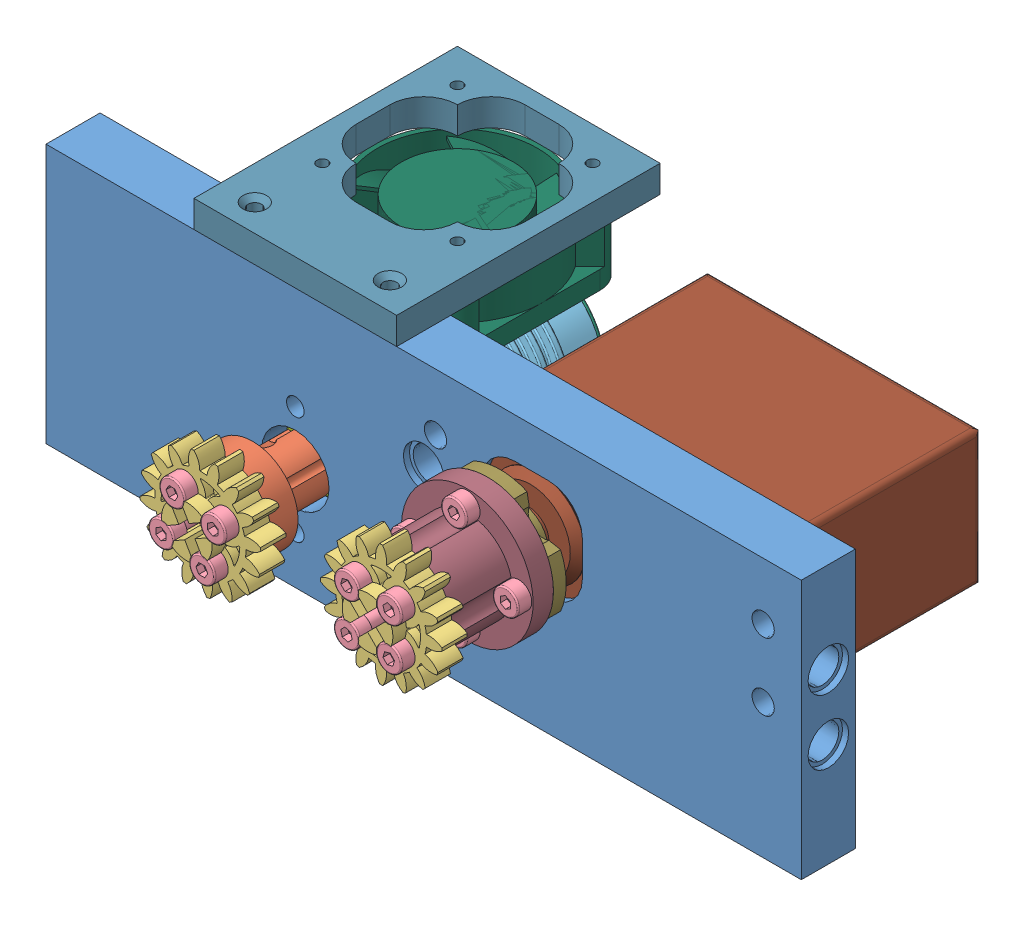
SolidWorks assembly Antriebseinheit, configuration Standard. Lengths in mm.
Overall size (111.8 42.91 67.55).
31 component instances, 15 part files, 21 mates.
Components (placement in the parent):
- Aufnahme-Motoren-1: Aufnahme-Motoren [Standard] x (-1 0 0) z (0 0 -1) size (111.8 38.4 8)
- Adapter-Motor-Zahnrad-16Z-1: Adapter-Motor-Zahnrad-16Z [Standard] at (-18.9984 15.2 10.3) x (-0.866025 -0.5 0) z (0 0 1) size (18 18 17.55)
  - Adapter-Motor-Zahnrad-16Z-1: Adapter-Motor-Zahnrad-16Z [Standard] at origin size (13.4 13.4 11.8)
  - Lego Zahnrad 16Z-1: Lego Zahnrad 16Z [Standard] at (0 0 5.875) size (18 18 7.75)
  - DIN 912 M2 x 6 --- 6N-1: DIN 912 M2 x 6 --- 6N [DIN 912 M2 x 6 --- 6N] at (0 4.425 9.75) x (0 0 -1) z (1 0 0) size (8 3.8 3.8)
  - DIN 912 M2 x 6 --- 6N-2: DIN 912 M2 x 6 --- 6N [DIN 912 M2 x 6 --- 6N] at (4.425 0 9.75) x (0 0 -1) z (0 -1 0) size (8 3.8 3.8)
  - DIN 912 M2 x 6 --- 6N-3: DIN 912 M2 x 6 --- 6N [DIN 912 M2 x 6 --- 6N] at (0 -4.425 9.75) x (0 0 -1) z (-1 0 0) size (8 3.8 3.8)
  - DIN 912 M2 x 6 --- 6N-4: DIN 912 M2 x 6 --- 6N [DIN 912 M2 x 6 --- 6N] at (-4.425 0 9.75) x (0 0 -1) z (0 1 0) size (8 3.8 3.8)
- Motor_B20-30-24S-FIN-1: Motor_B20-30-24S-FIN [Standard] at (-18.9984 15.2 -17) x (-0.866025 -0.5 0) z (0 0 1) size (23 23 51)
  - Motor_B20-30-24S-FIN-Gehaeuse-1: Motor_B20-30-24S-FIN-Gehaeuse [Standard] at origin size (23 23 29)
  - Motor_B20-30-24S-FIN-FlanschHinten-1: Motor_B20-30-24S-FIN-FlanschHinten [Standard] at (0 0 -15) x (0 -1 0) z (0 0 1) size (20 20 11)
  - Motor_B20-30-24S-FIN-FlanschVorne-1: Motor_B20-30-24S-FIN-FlanschVorne [Standard] at (0 0 14.5) x (0 -1 0) z (0 0 1) size (20 20 5)
  - Motor_B20-30-24S-FIN-Rotorwelle-1: Motor_B20-30-24S-FIN-Rotorwelle [Standard] at (0 0 -16.5) x (1 0 0) z (0 -1 0) size (5 45 5)
  - Motor_B20-30-24S-FIN-Lager-1: Motor_B20-30-24S-FIN-Lager [Standard] at (0 0 -12.5) x (0 0 -1) z (0 1 0) size (4 8 8)
  - Motor_B20-30-24S-FIN-Lager-2: Motor_B20-30-24S-FIN-Lager [Standard] at (0 0 16.5) x (0 0 -1) z (0 1 0) size (4 8 8)
  - Motor_B20-30-24S-FIN-Masse-1: Motor_B20-30-24S-FIN-Masse [Standard] at origin size (15 15 15)
- Servo HK15138-1: Servo HK15138 [Standard] at (26 24.95 -32.8) x (1 0 0) z (0 -1 0) size (55.5 41.1 20.15)
- Adapter-Servo-Zahnrad-16Z-1: Adapter-Servo-Zahnrad-16Z [Standard] at (15.75 24.95 8.5) size (27.58 27.58 22.65)
  - Servo-Horn-4er-modifiziert-1: Servo-Horn-4er-modifiziert [Standard] at origin size (19.5 19.5 5.7)
  - Adapter-Servo-Zahnrad-16Z-1: Adapter-Servo-Zahnrad-16Z [Standard] at (0 0 4.8) x (-0.707107 0.707107 0) z (0 0 1) size (19.5 19.5 12)
  - Lego Zahnrad 16Z-1: Lego Zahnrad 16Z [Standard] at (0 0 15.675) x (-0.707107 0.707107 0) z (0 0 1) size (18 18 7.75)
  - DIN 912 M2 x 6 --- 6N-1: DIN 912 M2 x 6 --- 6N [DIN 912 M2 x 6 --- 6N] at (-3.1289 -3.1289 19.55) x (0 0 -1) z (-0.707107 0.707107 0) size (8 3.8 3.8)
  - DIN 912 M2 x 6 --- 6N-2: DIN 912 M2 x 6 --- 6N [DIN 912 M2 x 6 --- 6N] at (-3.1289 3.1289 19.55) x (0 0 -1) z (0.707107 0.707107 0) size (8 3.8 3.8)
  - DIN 912 M2 x 6 --- 6N-3: DIN 912 M2 x 6 --- 6N [DIN 912 M2 x 6 --- 6N] at (3.1289 3.1289 19.55) x (0 0 -1) z (0.707107 -0.707107 0) size (8 3.8 3.8)
  - DIN 912 M2 x 6 --- 6N-4: DIN 912 M2 x 6 --- 6N [DIN 912 M2 x 6 --- 6N] at (3.1289 -3.1289 19.55) x (0 0 -1) z (-0.707107 -0.707107 0) size (8 3.8 3.8)
  - DIN 912 M2 x 6 --- 6N-5: DIN 912 M2 x 6 --- 6N [DIN 912 M2 x 6 --- 6N] at (0 7.65 6.8) x (0 0 -1) z (0 1 0) size (8 3.8 3.8)
  - DIN 912 M2 x 6 --- 6N-6: DIN 912 M2 x 6 --- 6N [DIN 912 M2 x 6 --- 6N] at (7.65 0 6.8) x (0 0 -1) z (1 0 0) size (8 3.8 3.8)
  - DIN 912 M2 x 6 --- 6N-7: DIN 912 M2 x 6 --- 6N [DIN 912 M2 x 6 --- 6N] at (0 -7.65 6.8) x (0 0 -1) z (0 -1 0) size (8 3.8 3.8)
  - DIN 912 M2 x 6 --- 6N-8: DIN 912 M2 x 6 --- 6N [DIN 912 M2 x 6 --- 6N] at (-7.65 0 6.8) x (0 0 -1) z (-1 0 0) size (8 3.8 3.8)
- Aufnahme-Lüfter-1: Aufnahme-Lüfter [Standard] at (-18.9984 38.4 -20) x (-1 0 0) z (0 0 -1) size (30 4 39)
- Hobby King X-Car 60A Brushless Car ESC - Lüfter-1: Hobby King X-Car 60A Brushless Car ESC - Lüfter [Ohne Stecker] at (-18.9984 28.1 -20) size (25.1 10.44 25.1)
Mates (geometry in assembly coordinates):
- Deckungsgleich1: coincident anti-aligned: plane of Aufnahme-Motoren-1 through (0 0 0) normal (0 0 -1); plane of assembly through (0 0 0) normal (0 0 1)
- Deckungsgleich2: coincident aligned: plane of Aufnahme-Motoren-1; plane of assembly through (0 0 0) normal (0 1 0)
- Deckungsgleich3: coincident anti-aligned: plane of Aufnahme-Motoren-1 through (0 0 0) normal (-1 0 0); plane of assembly through (0 0 0) normal (1 0 0)
- Deckungsgleich4: coincident anti-aligned: plane of Aufnahme-Motoren-1 through (0 0 -2) normal (0 0 -1); plane of Motor_B20-30-24S-FIN-1/Motor_B20-30-24S-FIN-FlanschVorne-1 through (-18.9984 15.2 -2) normal (0 0 1)
- Konzentrisch1: concentric anti-aligned: cylinder of Aufnahme-Motoren-1 through (-18.9984 23.2 4) axis (0 0 -1) radius 1.3; cylinder of Motor_B20-30-24S-FIN-1/Motor_B20-30-24S-FIN-FlanschVorne-1 through (-18.9984 23.2 -30.3945) axis (0 0 1) radius 1.0065
- Konzentrisch2: concentric anti-aligned: cylinder of Aufnahme-Motoren-1 through (-18.9984 7.2 4) axis (0 0 -1) radius 1.3; cylinder of Motor_B20-30-24S-FIN-1/Motor_B20-30-24S-FIN-FlanschVorne-1 through (-18.9984 7.2 -30.3945) axis (0 0 1) radius 1.0065
- Konzentrisch3: concentric anti-aligned: cylinder of Adapter-Motor-Zahnrad-16Z-1/Adapter-Motor-Zahnrad-16Z-1 through (-18.9984 15.2 2.5) axis (0 0 1) radius 1; cylinder of Motor_B20-30-24S-FIN-1/Motor_B20-30-24S-FIN-Rotorwelle-1 through (-18.9984 15.2 5.5) axis (0 0 -1) radius 1
- Abstand1: distance = 2 mm anti-aligned: plane of Motor_B20-30-24S-FIN-1/Motor_B20-30-24S-FIN-FlanschVorne-1 through (-18.9984 15.2 0.5) normal (0 0 1); plane of Adapter-Motor-Zahnrad-16Z-1/Adapter-Motor-Zahnrad-16Z-1 through (-18.9984 15.2 2.5) normal (0 0 -1)
- Deckungsgleich6: coincident anti-aligned: plane of Aufnahme-Motoren-1 through (0 0 3) normal (0 0 -1); plane of Servo HK15138-1 through (26 24.95 3) normal (0 0 1)
- Konzentrisch4: concentric anti-aligned: cylinder of Aufnahme-Motoren-1 through (1.75 19.95 -4) axis (0 0 -1) radius 1.65; cylinder of Servo HK15138-1 through (1.75 19.95 -6.5) axis (0 0 1) radius 2.1
- Konzentrisch5: concentric anti-aligned: cylinder of Aufnahme-Motoren-1 through (50.25 29.95 -4) axis (0 0 -1) radius 1.65; cylinder of Servo HK15138-1 through (50.25 29.95 -6.5) axis (0 0 1) radius 2.1
- Parallel1: parallel aligned: plane of Adapter-Motor-Zahnrad-16Z-1/Adapter-Motor-Zahnrad-16Z-1; plane of Motor_B20-30-24S-FIN-1/Motor_B20-30-24S-FIN-Rotorwelle-1 through (-19.2668 14.2367 11.5) normal (0.5 -0.866025 0)
- Konzentrisch6: concentric aligned: cylinder of Servo HK15138-1 through (15.75 24.95 3) axis (0 0 1) radius 2.9; cylinder of Adapter-Servo-Zahnrad-16Z-1/Servo-Horn-4er-modifiziert-1 through (15.75 24.95 8.5) axis (0 0 1) radius 1.6
- Abstand4: distance = 14.3 mm anti-aligned: plane of Adapter-Servo-Zahnrad-16Z-1/Servo-Horn-4er-modifiziert-1 through (15.75 29.45 10.3) normal (0 0 1); plane of Aufnahme-Motoren-1 through (0 0 -4) normal (0 0 -1)
- Deckungsgleich7: coincident: plane of Aufnahme-Motoren-1 through (55.9 38.4 -4) normal (0 1 0); plane of Aufnahme-Lüfter-1 through (-18.9984 38.4 -20) normal (0 -1 0)
- Konzentrisch7: concentric: cylinder of Aufnahme-Motoren-1 through (-8.9984 38.4 0) axis (0 1 0) radius 0.8; cylinder of Aufnahme-Lüfter-1 through (-8.9984 42.4 0) axis (0 1 0) radius 1
- Konzentrisch8: concentric aligned: cylinder of Aufnahme-Motoren-1 through (-28.9984 38.4 0) axis (0 1 0) radius 0.8; cylinder of Aufnahme-Lüfter-1 through (-28.9984 42.4 0) axis (0 1 0) radius 1
- Deckungsgleich8: coincident: plane of Aufnahme-Lüfter-1 through (-18.9984 38.4 -20) normal (0 -1 0); plane of Hobby King X-Car 60A Brushless Car ESC - Lüfter-1 through (-18.9984 38.4 -20) normal (0 1 0)
- Deckungsgleich9: coincident: plane of Aufnahme-Lüfter-1 through (-18.9984 38.4 -20) normal (-1 0 0); plane of Hobby King X-Car 60A Brushless Car ESC - Lüfter-1 through (-18.9984 28.1 -20) normal (1 0 0)
- Deckungsgleich10: coincident anti-aligned: plane of Aufnahme-Lüfter-1 through (-18.9984 38.4 -20) normal (0 0 -1); plane of Hobby King X-Car 60A Brushless Car ESC - Lüfter-1 through (-18.9984 28.1 -20) normal (0 0 1)
- Deckungsgleich11: coincident anti-aligned: plane of Servo HK15138-1 through (26 24.95 -32.8) normal (0 -1 0); plane of Adapter-Servo-Zahnrad-16Z-1/Servo-Horn-4er-modifiziert-1 through (15.75 24.95 8.5) normal (0 1 0)
